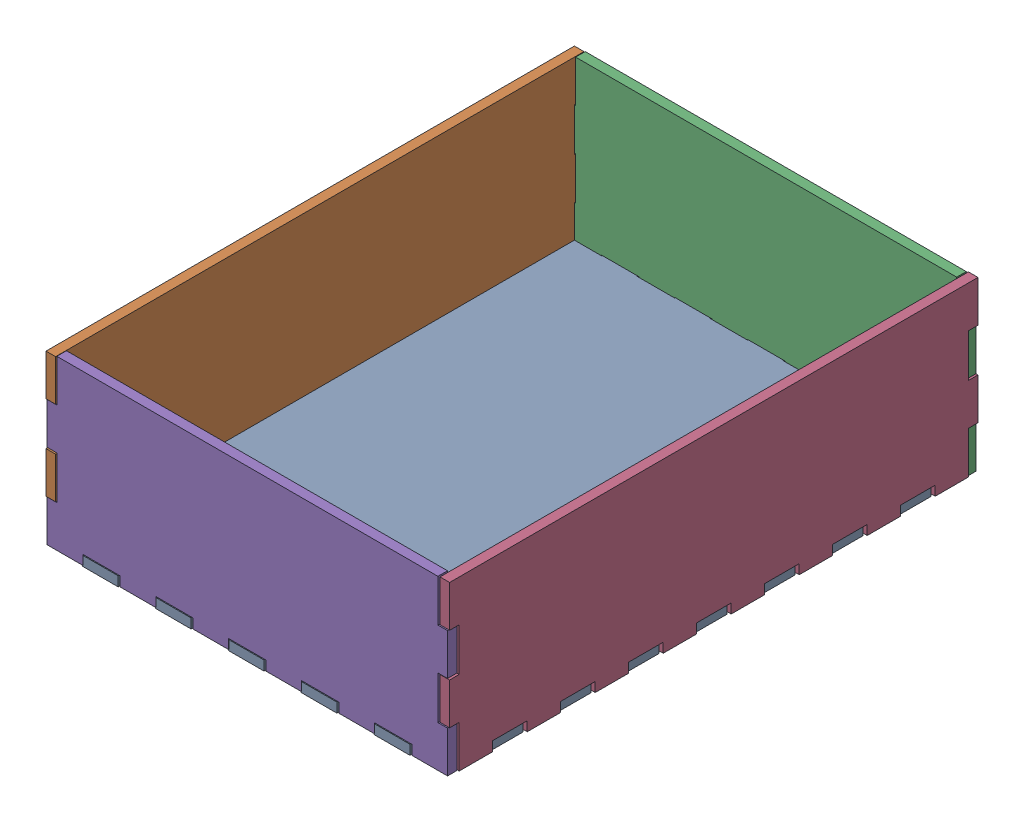
SolidWorks assembly eletrical_box, configuration Default. Lengths in mm.
Overall size (251.53 105.61 330.57).
5 component instances, 3 part files, 3 mates.
Components (placement in the parent):
- box_bottom-1: box_bottom [Default] x (0 0 1) z (0 1 0) size (330 250 6)
- box_long-1: box_long [Default] x (0 0 1) z (0 1 0) size (330 6 105)
- box_short-3: box_short [Default] at (250.7721 0.3879 330) x (0 0 -1) z (0 1 0) size (6 250 105)
- box_long-2: box_long [Default] at (245.5274 0.3436 -0.5404) x (0 0 1) z (0 1 0) size (330 6 105)
- box_short-4: box_short [Default] at (250.8015 0.609 654.0346) x (0 0 -1) z (0 1 0) size (6 250 105)
Mates (geometry in assembly coordinates):
- Coincident21: coincident anti-aligned: plane of box_bottom-1 through (0 0 112.1667) normal (-1 0 0)
- Coincident18: coincident anti-aligned: plane of box_long-1 through (0 0 0) normal (-1 0 0)
- Parallel19: parallel anti-aligned: plane of box_bottom-1 through (68.3182 0 6) normal (0 0 -1); plane of box_short-3 through (250.7721 0.3879 6) normal (0 0 1)
